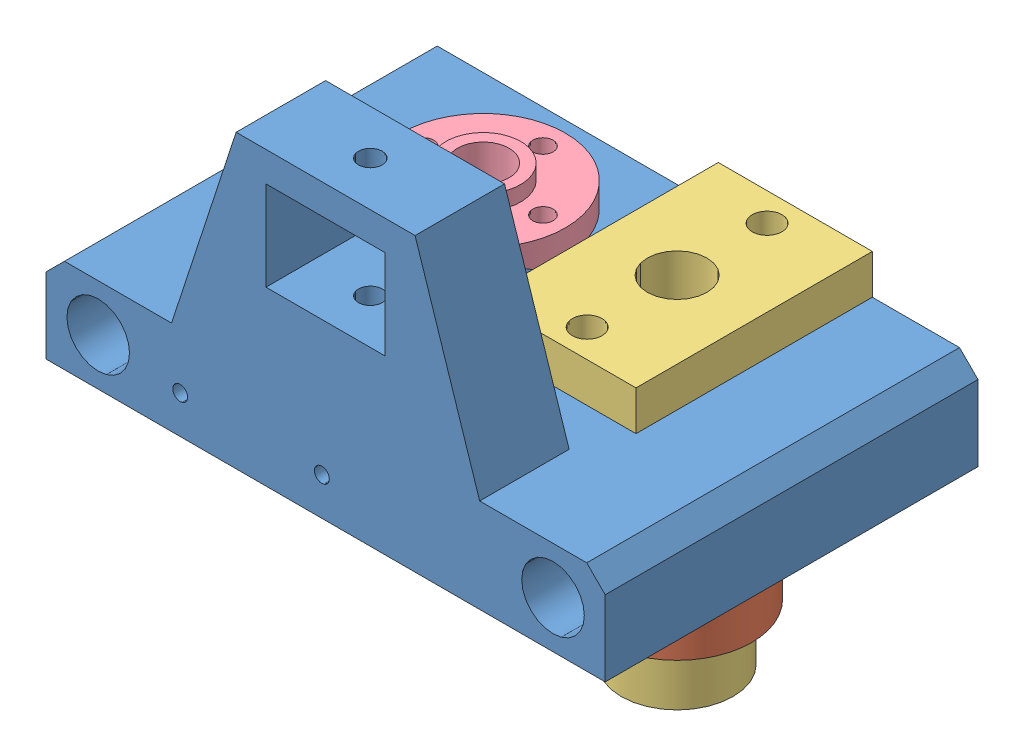
SolidWorks assembly _pulleyXAssem, configuration Default. Lengths in mm.
Overall size (75 66.38 50).
4 component instances, 4 part files, 8 mates.
Components (placement in the parent):
- xPulleyMount-1: xPulleyMount [Default] at (-23.2623 27.7759 84.2667) size (75 39.1 50)
- silverSliderBushing-1: silverSliderBushing [Default] at (27.2377 8.0259 50.1167) size (20 19.75 20)
- slider-1: slider [Default] at (16.9077 45.6959 65.9667) x (0 0 -1) z (-1 0 0) size (31.7 45.2 20.66)
- brassThing-1: brassThing [Default] at (1.2377 43.6959 50.1167) x (-1 0 0) z (0 0 1) size (22.02 10.35 22.02)
Mates (geometry in assembly coordinates):
- Coincident1: coincident: plane of xPulleyMount-1 through (-23.2623 27.7759 84.2667) normal (0 -1 0); plane of silverSliderBushing-1 through (27.2377 27.7759 50.1167) normal (0 1 0)
- Concentric1: concentric aligned: cylinder of xPulleyMount-1 through (27.2377 27.8759 50.1167) axis (0 -1 0) radius 7.9; cylinder of silverSliderBushing-1 through (27.2377 27.7759 50.1167) axis (0 -1 0) radius 7.9
- Coincident2: coincident: plane of xPulleyMount-1 through (-23.2623 40.3759 84.2667) normal (0 1 0); plane of brassThing-1 through (1.2377 40.3759 50.1167) normal (0 -1 0)
- Concentric2: concentric: cylinder of xPulleyMount-1 through (1.2377 27.8759 50.1167) axis (0 -1 0) radius 5.3; circle of brassThing-1
- Concentric3: concentric: cylinder of xPulleyMount-1 through (27.2377 27.8759 50.1167) axis (0 -1 0) radius 7.9; cylinder of slider-1 through (27.2377 0.4959 50.1167) axis (0 1 0) radius 7.5
- Coincident3: coincident: plane of xPulleyMount-1 through (-23.2623 40.3759 84.2667) normal (0 1 0); plane of slider-1 through (16.9077 40.3759 65.9667) normal (0 -1 0)
- Concentric4: concentric anti-aligned: cylinder of xPulleyMount-1 through (27.2377 27.7759 38.0517) axis (0 1 0) radius 2.2; cylinder of slider-1 through (27.2377 45.6959 38.0517) axis (0 -1 0) radius 2
- Concentric5: concentric anti-aligned: cylinder of xPulleyMount-1 through (1.2377 27.7759 42.1167) axis (0 1 0) radius 1.7; cylinder of brassThing-1 through (1.2377 43.6959 42.1167) axis (0 -1 0) radius 1.37
